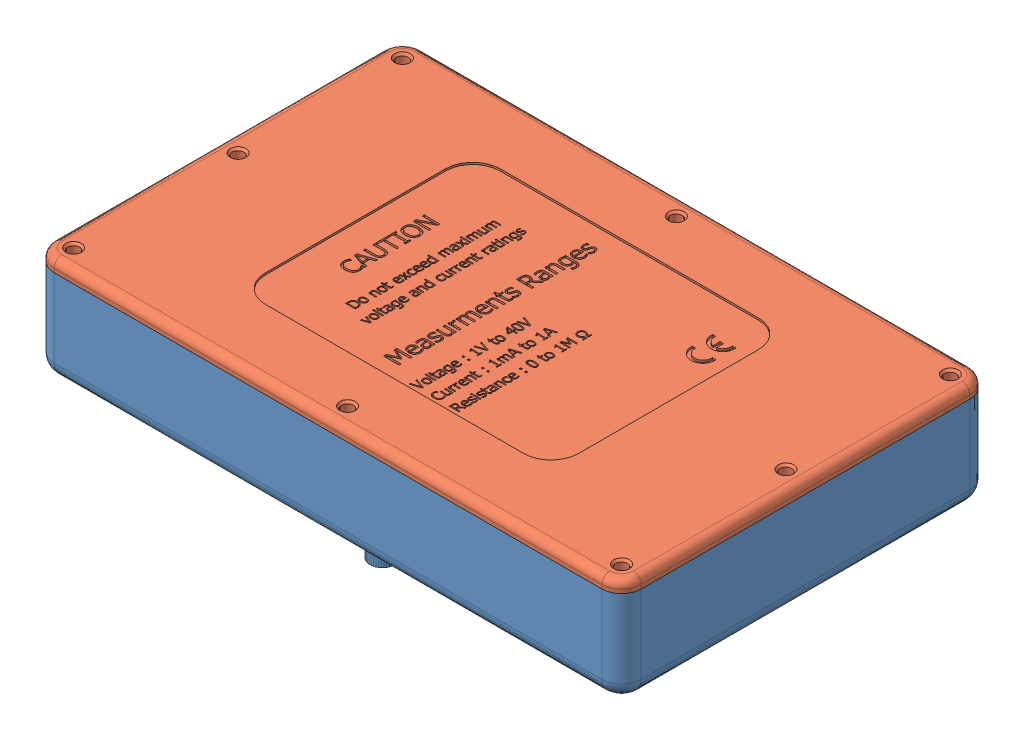
SolidWorks assembly Assem6, configuration Default. Lengths in mm.
Overall size (150 51 95.03).
2 component instances, 2 part files, 3 mates.
Components (placement in the parent):
- Front Assembly-1: Front Assembly [Default] at (44.0789 1.657 -17.8949) size (150 48.32 94)
- Back Assembly-1: Back Assembly [Default] at (24.4344 212.6368 23.5601) x (1 0 0) z (0 -1 0) size (150 95.03 8.45)
Mates (geometry in assembly coordinates):
- Concentric1: concentric: circle of Front Assembly-1; cylinder of Back Assembly-1 through (14.3701 101.2364 144.8036) axis (0 1 0) radius 1.5
- Coincident1: coincident: circle of Front Assembly-1; cylinder of Back Assembly-1 through (14.3701 101.2364 60.8036) axis (0 1 0) radius 1.5
- Coincident2: coincident anti-aligned: plane of Front Assembly-1 through (14.3701 98.2364 144.8036) normal (0 1 0); plane of Back Assembly-1 through (154.3701 98.2364 144.8036) normal (0 -1 0)
